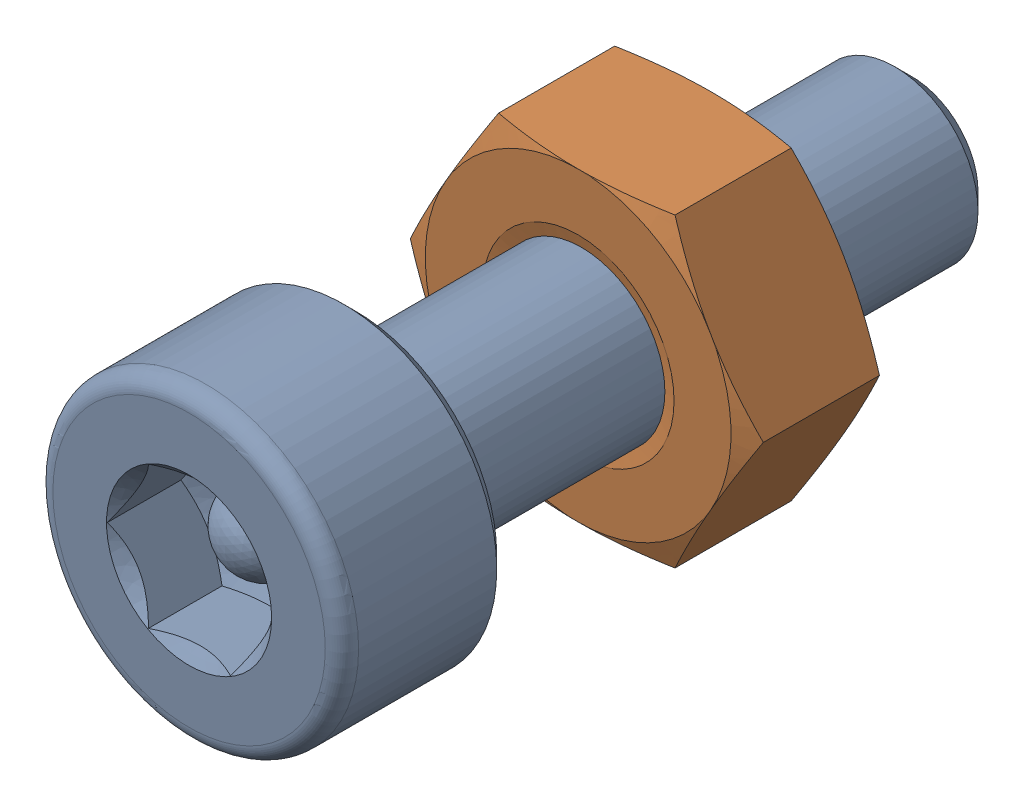
SolidWorks assembly Screw and Nut M3x010_018-1, configuration Varsayılan. Lengths in mm.
Overall size (6.35 5.5 13.14).
2 component instances, 2 part files, 0 mates.
Components (placement in the parent):
- M3x10-Screw017-1-1: M3x10-Screw017-1 [Varsayılan] at origin size (5.5 5.5 13.14)
- M3-Nut049-1-1: M3-Nut049-1 [Varsayılan] at (0 0 -4) x (-1 0 0) z (0 0 -1) size (6.35 5.5 2.4)
